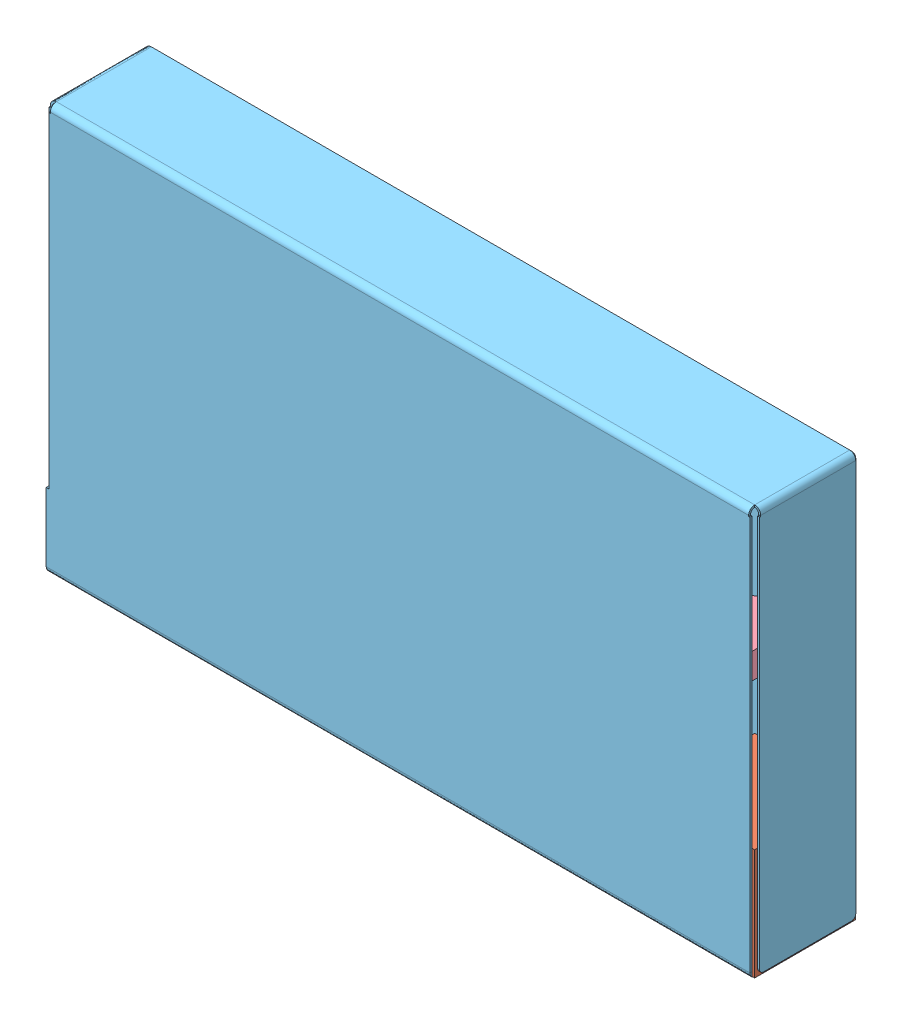
SolidWorks assembly muizenval, configuration Default. Lengths in mm.
Overall size (352 202 52.5).
5 component instances, 5 part files, 12 mates.
Components (placement in the parent):
- wip wap-1: wip wap [Default] at origin size (50 50 50)
- blokje-1: blokje [Default] at (150 27.5 0) size (50 55 50)
- draai cilinder-1: draai cilinder [Default] at (0 54.8412 -25) x (-0.986293 -0.165004 0) z (0 0 1) size (20 20 50)
- plank-2: plank [Default] at (-4.8683 68.8613 0) x (0.944668 0.328027 0) z (0 0 1) size (350 10 50)
- behuizing 2-1: behuizing 2 [Default] at (0 100 -25.5) x (0 0 1) z (-1 0 0) size (52.5 202 352)
Mates (geometry in assembly coordinates):
- Coincident4: coincident aligned: plane of wip wap-1 through (-25 0 25) normal (0 -1 0); plane of blokje-1 through (175 0 25) normal (0 -1 0)
- Distance2: distance = 100 mm: line of blokje-1 through (125 0 25) axis (0 0 -1); moEndPointRef_w of wip wap-1
- Concentric1: concentric aligned: cylinder of wip wap-1 through (0 54.8412 25) axis (0 0 -1) radius 10; cylinder of draai cilinder-1 through (0 54.8412 25) axis (0 0 -1) radius 10
- Coincident11: coincident aligned: plane of wip wap-1 through (0 54.8412 25) normal (0 0 1); plane of draai cilinder-1 through (0 54.8412 25) normal (0 0 1)
- Concentric2: concentric aligned: cylinder of draai cilinder-1 through (0 54.8412 25) axis (0 0 -1) radius 10; cylinder of plank-2 through (0 54.8412 25) axis (0 0 -1) radius 10
- Coincident14: coincident: plane of blokje-1 through (150 27.5 -25) normal (0 0 -1); line of plank-2 through (163.7289 116.8193 -25) axis (-0.328027 0.944668 0)
- Coincident24: coincident aligned: plane of draai cilinder-1 through (0 54.8412 -25) normal (0 0 -1); plane of plank-2 through (0 54.8412 -25) normal (0 0 -1)
- Coincident25: coincident aligned: plane of blokje-1 through (150 27.5 25) normal (0 0 1); plane of plank-2 through (0 54.8412 25) normal (0 0 1)
- Coincident26: coincident aligned: plane of wip wap-1 through (0 54.8412 25) normal (0 0 1); plane of plank-2 through (0 54.8412 25) normal (0 0 1)
- Coincident27: coincident anti-aligned: plane of blokje-1 through (175 55 25) normal (1 0 0); plane of behuizing 2-1 through (175 0 25) normal (-1 0 0)
- Coincident28: coincident anti-aligned: plane of blokje-1 through (150 27.5 25) normal (0 0 1); plane of behuizing 2-1 through (0 100 25) normal (0 0 -1)
- Coincident29: coincident anti-aligned: plane of wip wap-1 through (-25 0 25) normal (0 -1 0); plane of behuizing 2-1 through (175 0 25) normal (0 1 0)
